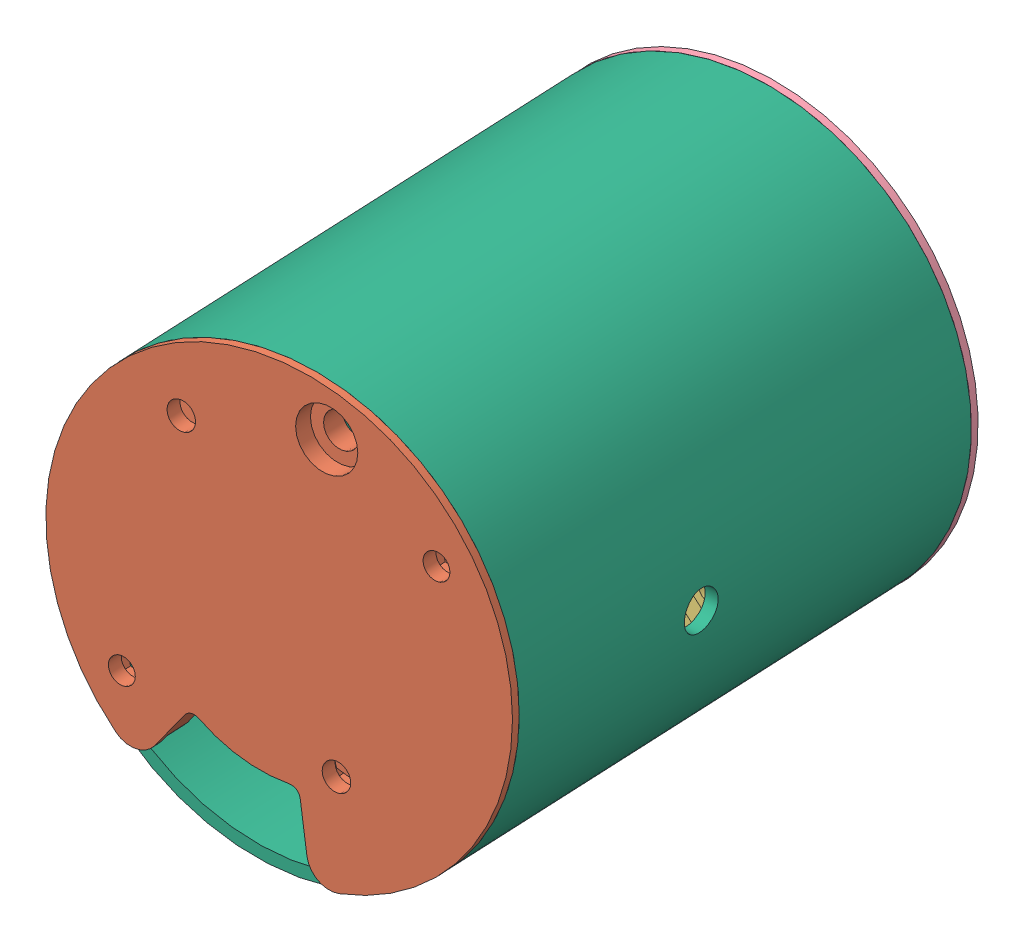
SolidWorks assembly single_bot, configuration Default. Lengths in mm.
Overall size (74.03 71.43 77.62).
9 component instances, 6 part files, 16 mates.
Components (placement in the parent):
- erm-1: erm [Default] at (41.2799 -60.4787 168.1252) x (0.966215 -0.245475 -0.078549) z (0.093461 0.049683 0.994383) size (8.7 8.7 25)
- erm-2: erm [Default] at (4.6876 -52.42 171.1618) x (-0.995567 -0.005939 0.093869) z (0.093461 0.049683 0.994383) size (8.7 8.7 25)
- top ring.0011-1: top ring.0011 [Default] at (27.0872 -61.9516 233.6931) x (-0.209154 -0.975488 0.068398) z (0.093461 0.049683 0.994383) size (53.82 57.15 31.48)
- pump_holder-1: pump_holder [Default] at (23.7413 -63.7303 198.0942) x (0.209154 0.975488 -0.068398) z (0.093461 0.049683 0.994383) size (45.7 53.98 18.24)
- botom_cap_r1-1: botom_cap_r1 [Default] at (20.9188 -65.2307 168.0639) x (0.973406 -0.214372 -0.080779) z (0.093461 0.049683 0.994383) size (57.15 57.15 12)
- semi_sphere_3_8th_inch-1: semi_sphere_3_8th_inch [Default] at (41.2799 -60.4787 168.1252) x (-0.630477 0.775938 0.020489) z (-0.093461 -0.049683 -0.994383) size (9 9 4.5)
- semi_sphere_3_8th_inch-2: semi_sphere_3_8th_inch [Default] at (4.6876 -52.42 171.1618) x (0.424561 0.901406 -0.084942) z (-0.093461 -0.049683 -0.994383) size (9 9 4.5)
- semi_sphere_3_8th_inch-3: semi_sphere_3_8th_inch [Default] at (16.8744 -84.9434 171.6414) x (-0.285449 0.958163 -0.021045) z (-0.093461 -0.049683 -0.994383) size (9 9 4.5)
- cover-1: cover [Default] at (21.0123 -65.1811 169.0583) x (0.99562 -0.002328 -0.093461) z (0.093461 0.049683 0.994383) size (57.15 57.15 67)
Mates (geometry in assembly coordinates):
- Concentric21: concentric aligned: cylinder of botom_cap_r1-1 through (21.0123 -65.1811 169.0583) axis (0.093461 0.049683 0.994383) radius 27.3625; cylinder of cover-1 through (21.0123 -65.1811 169.0583) axis (0.093461 0.049683 0.994383) radius 26.9875
- Coincident22: coincident anti-aligned: plane of botom_cap_r1-1 through (-12.7912 -86.9376 173.3225) normal (0.093461 0.049683 0.994383); plane of cover-1 through (21.0123 -65.1811 169.0583) normal (-0.093461 -0.049683 -0.994383)
- Concentric22: concentric anti-aligned: cylinder of pump_holder-1 through (24.0217 -63.5813 201.0774) axis (-0.093461 -0.049683 -0.994383) radius 26.9875; cylinder of cover-1 through (21.0123 -65.1811 169.0583) axis (0.093461 0.049683 0.994383) radius 26.9875
- Concentric23: concentric anti-aligned: cylinder of top ring.0011-1 through (27.2742 -61.8523 235.6819) axis (-0.093461 -0.049683 -0.994383) radius 27.3625; cylinder of cover-1 through (21.0123 -65.1811 169.0583) axis (0.093461 0.049683 0.994383) radius 26.9875
- Coincident23: coincident anti-aligned: plane of top ring.0011-1 through (-10.4482 -79.6408 240.1162) normal (-0.093461 -0.049683 -0.994383); plane of cover-1 through (27.2742 -61.8523 235.6819) normal (0.093461 0.049683 0.994383)
- Concentric24: concentric aligned: cylinder of erm-2 through (7.0242 -51.1779 196.0214) axis (-0.093461 -0.049683 -0.994383) radius 4.35; cylinder of pump_holder-1 through (7.0242 -51.1779 196.0214) axis (-0.093461 -0.049683 -0.994383) radius 4.5
- Coincident24: coincident anti-aligned: plane of erm-2 through (11.3188 -46.7975 195.3988) normal (0.093461 0.049683 0.994383); plane of pump_holder-1 through (12.392 -47.5843 195.3373) normal (-0.093461 -0.049683 -0.994383)
- Concentric25: concentric aligned: cylinder of erm-1 through (43.6165 -59.2366 192.9847) axis (-0.093461 -0.049683 -0.994383) radius 4.35; cylinder of pump_holder-1 through (43.8034 -59.1372 194.9735) axis (-0.093461 -0.049683 -0.994383) radius 5.5
- Coincident25: coincident anti-aligned: plane of erm-1 through (38.3565 -62.3874 193.6365) normal (0.093461 0.049683 0.994383); plane of pump_holder-1 through (48.9711 -55.6401 192.3018) normal (-0.093461 -0.049683 -0.994383)
- Coincident26: coincident anti-aligned: plane of erm-1 through (44.4454 -65.77 168.092) normal (-0.093461 -0.049683 -0.994383); plane of semi_sphere_3_8th_inch-1 through (34.9613 -59.8153 168.6859) normal (0.093461 0.049683 0.994383)
- Concentric26: concentric anti-aligned: circle of erm-1; circle of semi_sphere_3_8th_inch-1
- Coincident27: coincident anti-aligned: plane of erm-2 through (0.3009 -48.0914 171.3578) normal (-0.093461 -0.049683 -0.994383); plane of semi_sphere_3_8th_inch-2 through (2.5409 -46.4149 171.0635) normal (0.093461 0.049683 0.994383)
- Concentric27: concentric anti-aligned: circle of erm-2; circle of semi_sphere_3_8th_inch-2
- Coincident28: coincident anti-aligned: plane of botom_cap_r1-1 through (21.7414 -86.0152 171.2375) normal (-0.093461 -0.049683 -0.994383); plane of semi_sphere_3_8th_inch-3 through (11.2853 -81.8933 172.0143) normal (0.093461 0.049683 0.994383)
- Concentric28: concentric aligned: circle of botom_cap_r1-1; circle of semi_sphere_3_8th_inch-3
- Coincident29: coincident aligned: plane of botom_cap_r1-1 through (21.7414 -86.0152 171.2375) normal (-0.093461 -0.049683 -0.994383); circle of semi_sphere_3_8th_inch-1
